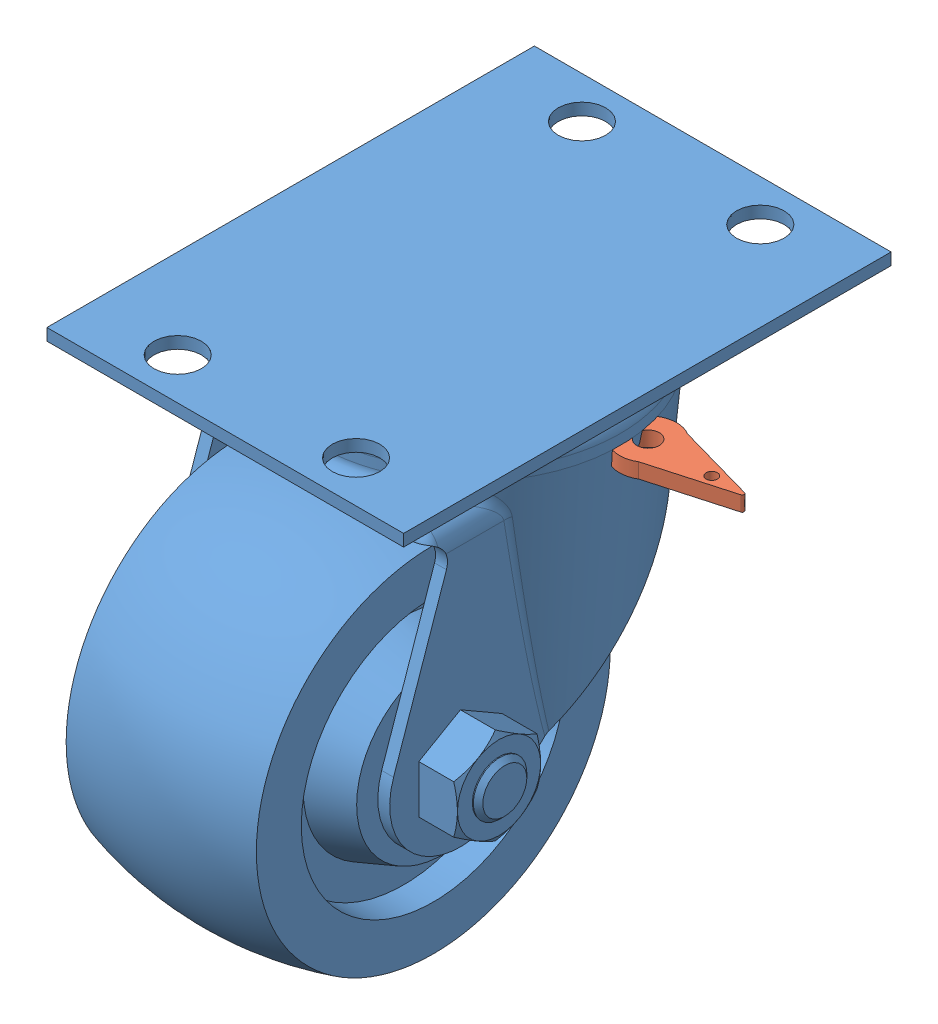
SolidWorks assembly Steerable Caster, configuration Default. Lengths in mm.
Overall size (57.95 63.5 75.41).
2 component instances, 2 part files, 3 mates.
Components (placement in the parent):
- Caster-1: Caster [78155T41] at (27.6965 30.7677 63.95) size (47.62 63.5 75.41)
- SteeringServoHead-1: SteeringServoHead [Default] at (49.0103 58.9487 43.8873) x (0 0 -1) z (1 0 0) size (7.62 2 14.89)
Mates (geometry in assembly coordinates):
- Parallel1: parallel anti-aligned: plane of SteeringServoHead-1 through (46.9351 61.4887 38.4566) normal (-1 0 0); plane of assembly through (0 0 0) normal (1 0 0)
- Perpendicular2: perpendicular: plane of SteeringServoHead-1 through (46.9351 61.4887 38.4566) normal (-1 0 0); plane of assembly through (0 0 0) normal (0 0 1)
- Parallel4: parallel aligned: plane of SteeringServoHead-1 through (49.0103 60.9487 43.8873) normal (0 1 0); plane of assembly through (0 0 0) normal (0 1 0)
